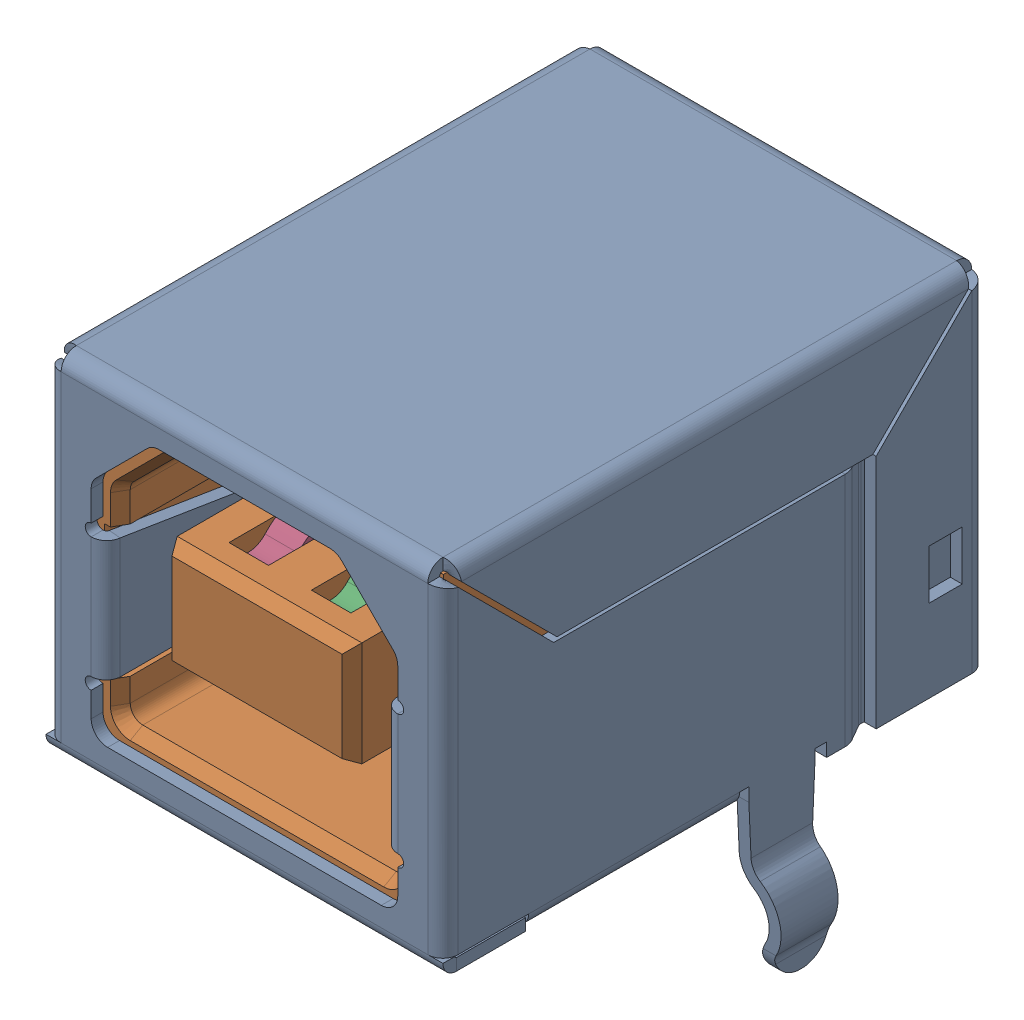
SolidWorks assembly USB type b, configuration Default. Lengths in mm.
Overall size (13.72 15.2 16.5).
6 component instances, 4 part files, 0 mates.
Components (placement in the parent):
- USB SHELL-1: USB SHELL [Default] at origin size (13.72 15.2 16.5)
- USB core-1: USB core [Default] at origin size (11.3 10.68 15.75)
- usb top contact-1: usb top contact [Default] at (1.25 6.09 -0.38) size (1 9.67 13.76)
- usb top contact-2: usb top contact [Default] at (-1.25 6.09 -0.38) size (1 9.67 13.76)
- usb btm contact-1: usb btm contact [Default] at (1.25 4.41 -0.38) size (1 6.84 11.76)
- usb btm contact-2: usb btm contact [Default] at (-1.25 4.41 -0.38) size (1 6.84 11.76)
